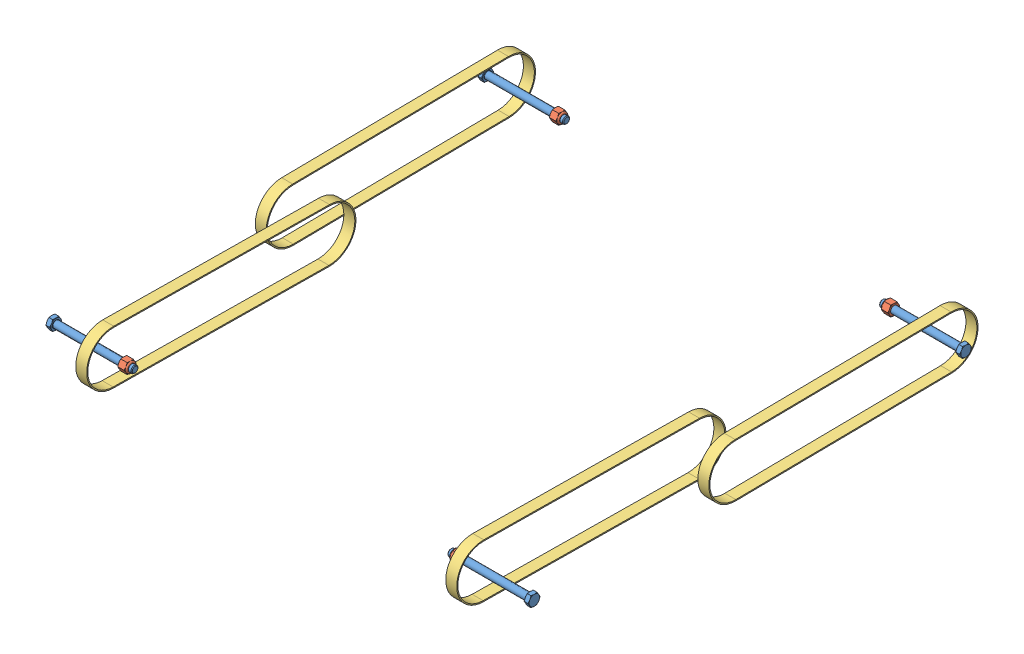
SolidWorks assembly LONG CHASIS.STEP, configuration Default. Lengths in mm.
Overall size (660.06 77.51 664.05).
19 component instances, 3 part files, 0 mates.
Components (placement in the parent):
- AM14U5 Configurable Gearboxes_Long _TB Mini_6wD Churro Locations.STEP-1: AM14U5 Configurable Gearboxes_Long _TB Mini_6wD Churro Locations.STEP [Default] at origin (suppressed, hidden)
- 2022 6 HiGrip with hub and double pulley.STEP-1: 2022 6 HiGrip with hub and double pulley.STEP [Default] at (-96.3242 -81.1238 258.7405) x (1 0 0) z (0 -0.377652 0.925948) (suppressed, hidden)
- 2022 6 HiGrip with bearings, pulleys and spacers.STEP-1: 2022 6 HiGrip with bearings, pulleys and spacers.STEP [Default] at (-96.7941 92.575 150.502) x (1 0 0) z (0 -0.726066 -0.687625) (suppressed, hidden)
- 2022 6 HiGrip with bearings, pulleys and spacers-1.STEP-1: 2022 6 HiGrip with bearings, pulleys and spacers-1.STEP [Default] at (-33.3809 -205.351 740.6027) x (-1 0 0) z (0 0.726066 -0.687625) (suppressed, hidden)
- 2022 6 HiGrip with bearings, pulleys and spacers-2.STEP-1: 2022 6 HiGrip with bearings, pulleys and spacers-2.STEP [Default] at (-652.4191 -13.1296 558.5582) x (1 0 0) z (0 -0.726066 0.687625) (suppressed, hidden)
- 2022 6 HiGrip with hub and double pulley-1.STEP-1: 2022 6 HiGrip with hub and double pulley-1.STEP [Default] at (-589.4758 -181.1047 503.8794) x (-1 0 0) z (0 0.377652 -0.925948) (suppressed, hidden)
- 2022 6 HiGrip with bearings, pulleys and spacers-3.STEP-1: 2022 6 HiGrip with bearings, pulleys and spacers-3.STEP [Default] at (-589.0059 -99.6464 -31.5425) x (-1 0 0) z (0 0.726066 0.687625) (suppressed, hidden)
- 375-16 x 4.25 Hex Bolt_HFBOLT 0.375-16x2.5x1-C.STEP-1: 375-16 x 4.25 Hex Bolt_HFBOLT 0.375-16x2.5x1-C.STEP [Default] at (-12.8778 -56.388 115.2866) x (-1 0 0) z (0 1 0) size (114.13 16.49 16.5)
- 375-16 Lock Nut_91831A127.STEP-1: 375-16 Lock Nut_91831A127.STEP [Default] at (-111.125 -56.388 115.2866) x (0 0.5 -0.866025) z (0 0.866025 0.5) size (14.29 11.52 16.5)
- 800-5M-15 v2.STEP-1: 800-5M-15 v2.STEP [Default] at (-32.8924 -59.9444 410.337) x (0 0.012053 -0.999927) z (0 0.999927 0.012053) size (368.15 15 73.08)
- 800-5M-15 v2.STEP-2: 800-5M-15 v2.STEP [Default] at (-82.4477 -59.9444 410.337) x (0 0.012053 0.999927) z (0 -0.999927 0.012053) size (368.15 15 73.08)
- 375-16 x 4.25 Hex Bolt_HFBOLT 0.375-16x2.5x1-C.STEP-2: 375-16 x 4.25 Hex Bolt_HFBOLT 0.375-16x2.5x1-C.STEP [Default] at (-12.8778 -56.388 705.3874) x (-1 0 0) z (0 -1 0) size (114.13 16.49 16.5)
- 375-16 Lock Nut_91831A127.STEP-2: 375-16 Lock Nut_91831A127.STEP [Default] at (-111.125 -56.388 705.3874) x (0 -0.5 -0.866025) z (0 0.866025 -0.5) size (14.29 11.52 16.5)
- 800-5M-15 v2.STEP-3: 800-5M-15 v2.STEP [Default] at (-603.3523 -59.9444 410.337) x (0 0.012053 0.999927) z (0 0.999927 -0.012053) size (368.15 15 73.08)
- 375-16 x 4.25 Hex Bolt_HFBOLT 0.375-16x2.5x1-C.STEP-3: 375-16 x 4.25 Hex Bolt_HFBOLT 0.375-16x2.5x1-C.STEP [Default] at (-672.9222 -56.388 115.2866) x (1 0 0) z (0 -1 0) size (114.13 16.49 16.5)
- 375-16 Lock Nut_91831A127.STEP-3: 375-16 Lock Nut_91831A127.STEP [Default] at (-574.675 -56.388 115.2866) x (0 -0.5 0.866025) z (0 0.866025 0.5) size (14.29 11.52 16.5)
- 375-16 Lock Nut_91831A127.STEP-4: 375-16 Lock Nut_91831A127.STEP [Default] at (-574.675 -56.388 705.3874) x (0 0.5 0.866025) z (0 0.866025 -0.5) size (14.29 11.52 16.5)
- 375-16 x 4.25 Hex Bolt_HFBOLT 0.375-16x2.5x1-C.STEP-4: 375-16 x 4.25 Hex Bolt_HFBOLT 0.375-16x2.5x1-C.STEP [Default] at (-672.9222 -56.388 705.3874) x (1 0 0) z (0 1 0) size (114.13 16.49 16.5)
- 800-5M-15 v2.STEP-4: 800-5M-15 v2.STEP [Default] at (-652.9076 -59.9444 410.337) x (0 0.012053 -0.999927) z (0 -0.999927 -0.012053) size (368.15 15 73.08)
